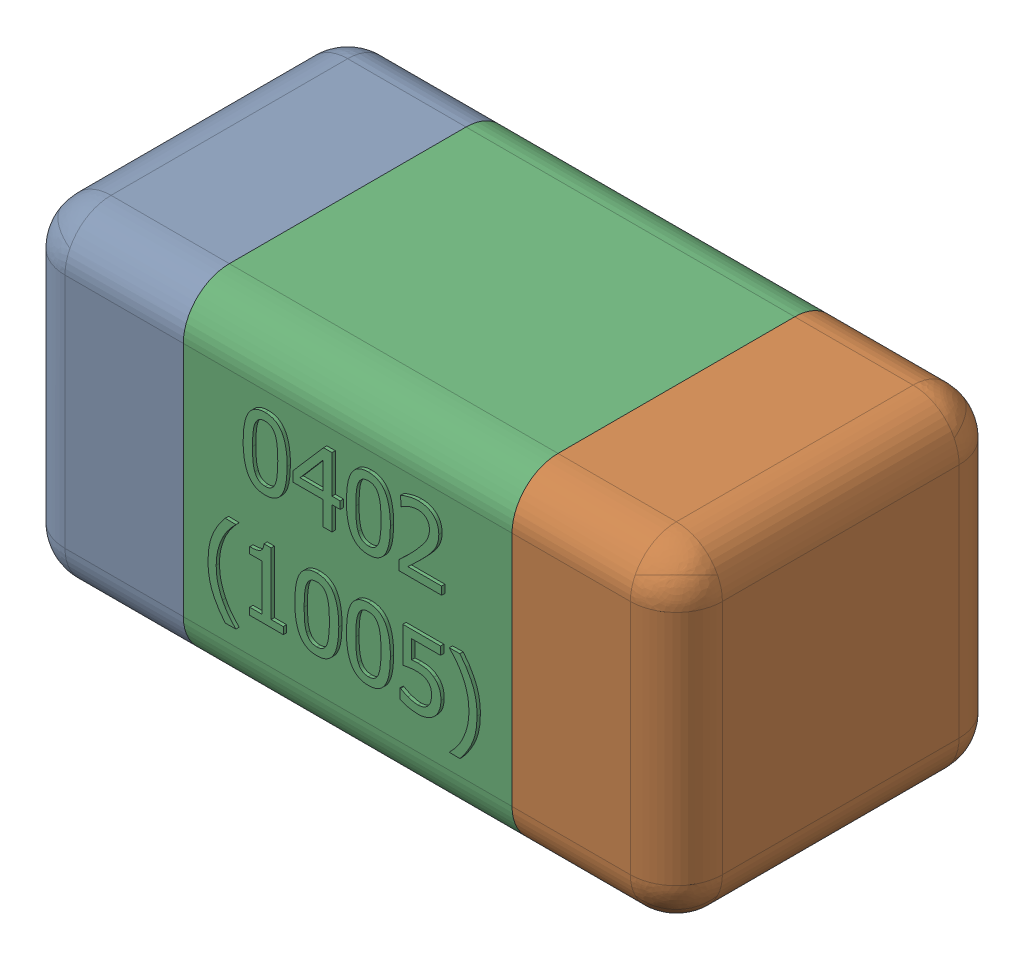
SolidWorks assembly C51, configuration Standard. Lengths in mm.
Overall size (1.01 0.51 0.51).
4 component instances, 3 part files, 0 mates.
Components (placement in the parent):
- C51-subassembly-1-1: C51-subassembly-1 [Standard] at (11.6001 -0.9 0) x (1 0 0) z (0 0 1) size (1.01 0.51 0.51)
  - User Library-0402_Cap-1: User Library-0402_Cap [Standard] at origin size (0.26 0.51 0.51)
  - User Library-0402_Cap-1-1: User Library-0402_Cap-1 [Standard] at origin size (0.26 0.5 0.51)
  - User Library-0402_Cap-2-1: User Library-0402_Cap-2 [Standard] at origin size (0.5 0.5 0.51)
